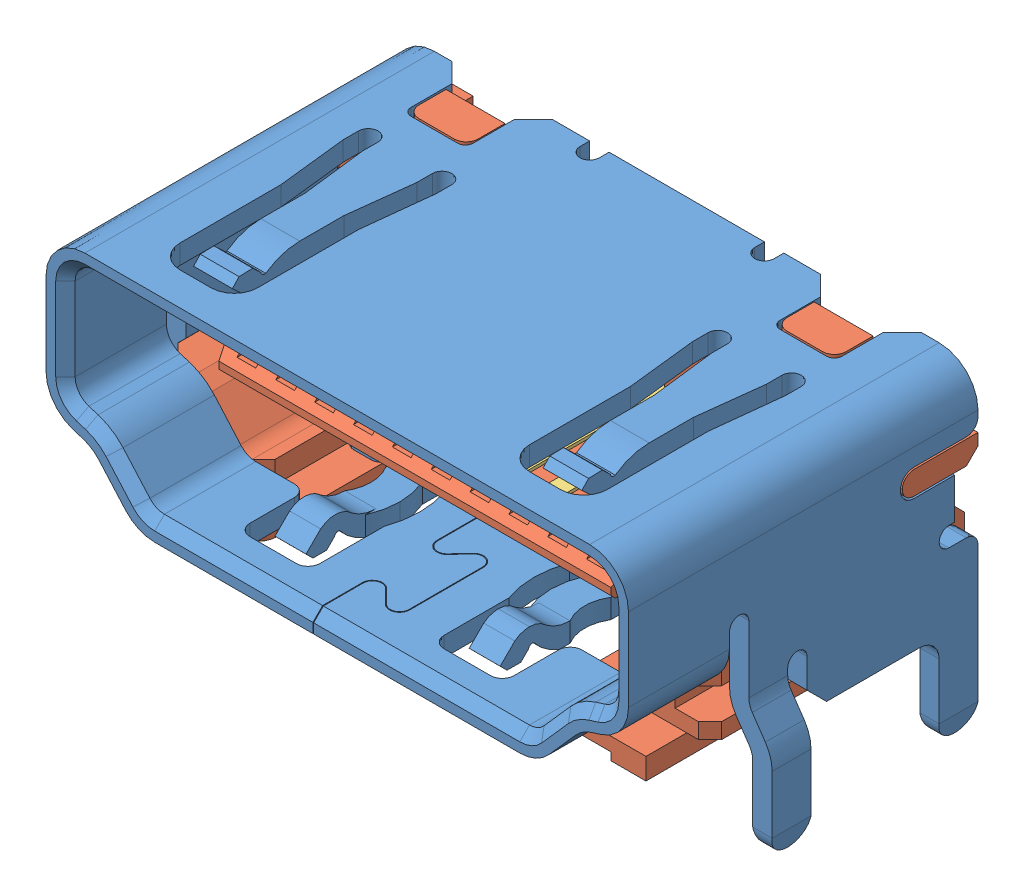
SolidWorks assembly HDMI_socket, configuration Défaut. Lengths in mm.
Overall size (16.2 8 9.9).
22 component instances, 4 part files, 0 mates.
Components (placement in the parent):
- HDMI_socket.STEP-1: HDMI_socket.STEP [Défaut] at origin size (16.2 8 9.9)
  - HDMI_socket_cover.STEP-1: HDMI_socket_cover.STEP [Défaut] at (-20 0 0) size (16.2 8 9)
  - HDMI_socket_inside.STEP-1: HDMI_socket_inside.STEP [Défaut] at (-20 0 0) size (15 6.1 7.6)
  - HDMI_socket_large_pin.STEP-1: HDMI_socket_large_pin.STEP [Défaut] at (-201.7661 0.45 76.5103) x (0 0 -1) z (0 -1 0) size (7.55 0.65 3.84)
  - HDMI_socket_small_pin.STEP-1: HDMI_socket_small_pin.STEP [Défaut] at (-202.2661 -0.25 76.5103) x (0 0 -1) z (0 -1 0) size (7.55 0.65 3.08)
  - HDMI_socket_large_pin.STEP-2: HDMI_socket_large_pin.STEP [Défaut] at (-202.7661 0.45 76.5103) x (0 0 -1) z (0 -1 0) size (7.55 0.65 3.84)
  - HDMI_socket_large_pin.STEP-3: HDMI_socket_large_pin.STEP [Défaut] at (-203.7661 0.45 76.5103) x (0 0 -1) z (0 -1 0) size (7.55 0.65 3.84)
  - HDMI_socket_large_pin.STEP-4: HDMI_socket_large_pin.STEP [Défaut] at (-204.7661 0.45 76.5103) x (0 0 -1) z (0 -1 0) size (7.55 0.65 3.84)
  - HDMI_socket_large_pin.STEP-5: HDMI_socket_large_pin.STEP [Défaut] at (-205.7661 0.45 76.5103) x (0 0 -1) z (0 -1 0) size (7.55 0.65 3.84)
  - HDMI_socket_large_pin.STEP-6: HDMI_socket_large_pin.STEP [Défaut] at (-206.7661 0.45 76.5103) x (0 0 -1) z (0 -1 0) size (7.55 0.65 3.84)
  - HDMI_socket_large_pin.STEP-7: HDMI_socket_large_pin.STEP [Défaut] at (-207.7661 0.45 76.5103) x (0 0 -1) z (0 -1 0) size (7.55 0.65 3.84)
  - HDMI_socket_large_pin.STEP-8: HDMI_socket_large_pin.STEP [Défaut] at (-208.7661 0.45 76.5103) x (0 0 -1) z (0 -1 0) size (7.55 0.65 3.84)
  - HDMI_socket_large_pin.STEP-9: HDMI_socket_large_pin.STEP [Défaut] at (-209.7661 0.45 76.5103) x (0 0 -1) z (0 -1 0) size (7.55 0.65 3.84)
  - HDMI_socket_large_pin.STEP-10: HDMI_socket_large_pin.STEP [Défaut] at (-210.7661 0.45 76.5103) x (0 0 -1) z (0 -1 0) size (7.55 0.65 3.84)
  - HDMI_socket_small_pin.STEP-2: HDMI_socket_small_pin.STEP [Défaut] at (-203.2661 -0.25 76.5103) x (0 0 -1) z (0 -1 0) size (7.55 0.65 3.08)
  - HDMI_socket_small_pin.STEP-3: HDMI_socket_small_pin.STEP [Défaut] at (-204.2661 -0.25 76.5103) x (0 0 -1) z (0 -1 0) size (7.55 0.65 3.08)
  - HDMI_socket_small_pin.STEP-4: HDMI_socket_small_pin.STEP [Défaut] at (-205.2661 -0.25 76.5103) x (0 0 -1) z (0 -1 0) size (7.55 0.65 3.08)
  - HDMI_socket_small_pin.STEP-5: HDMI_socket_small_pin.STEP [Défaut] at (-206.2661 -0.25 76.5103) x (0 0 -1) z (0 -1 0) size (7.55 0.65 3.08)
  - HDMI_socket_small_pin.STEP-6: HDMI_socket_small_pin.STEP [Défaut] at (-207.2661 -0.25 76.5103) x (0 0 -1) z (0 -1 0) size (7.55 0.65 3.08)
  - HDMI_socket_small_pin.STEP-7: HDMI_socket_small_pin.STEP [Défaut] at (-208.2661 -0.25 76.5103) x (0 0 -1) z (0 -1 0) size (7.55 0.65 3.08)
  - HDMI_socket_small_pin.STEP-8: HDMI_socket_small_pin.STEP [Défaut] at (-209.2661 -0.25 76.5103) x (0 0 -1) z (0 -1 0) size (7.55 0.65 3.08)
  - HDMI_socket_small_pin.STEP-9: HDMI_socket_small_pin.STEP [Défaut] at (-210.2661 -0.25 76.5103) x (0 0 -1) z (0 -1 0) size (7.55 0.65 3.08)
